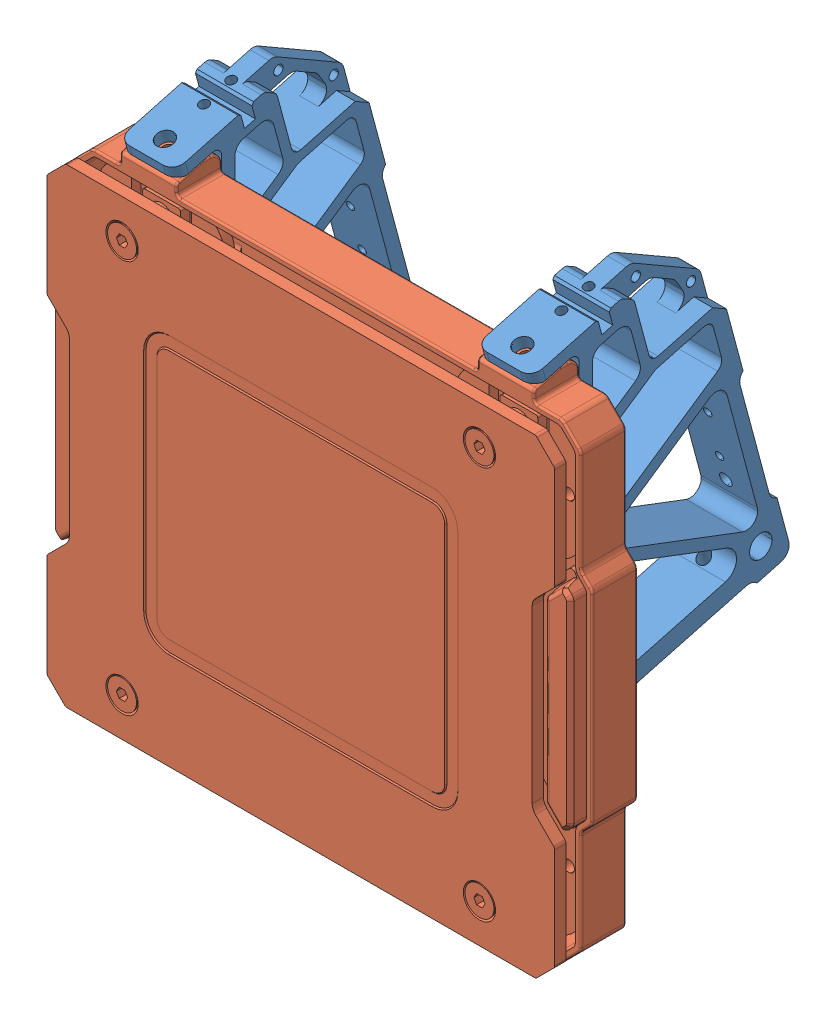
SolidWorks assembly 装配体1, configuration 默认. Lengths in mm.
Overall size (141 139.39 74.83).
3 component instances, 2 part files, 6 mates.
Components (placement in the parent):
- RM2019裁判系统支撑架AH02-1: RM2019裁判系统支撑架AH02 [默认] at (-15.033 -31.1753 152.6103) size (15 130.97 68.39)
- RM2019裁判系统装甲模块AM02-1: RM2019裁判系统装甲模块AM02 [默认] at (-107.5374 -73.9899 179.5172) x (0 0 1) z (-1 0 0) size (19 129.97 141)
- RM2019裁判系统支撑架AH02-2: RM2019裁判系统支撑架AH02 [默认] at (-110.033 -31.1753 152.6103) size (15 130.97 68.39)
Mates (geometry in assembly coordinates):
- 重合1: coincident: plane of assembly; plane of assembly; plane of RM2019裁判系统支撑架AH02-1 through (-7.533 58.8247 152.6103) normal (0 0 1); plane of RM2019裁判系统装甲模块AM02-1 through (-62.533 -10.0287 152.6103) normal (0 0 -1)
- 重合2: coincident: plane of assembly; plane of assembly; plane of RM2019裁判系统装甲模块AM02-1 through (-62.533 -10.0287 152.6103) normal (0 0 -1); plane of RM2019裁判系统支撑架AH02-2 through (-102.533 58.8247 152.6103) normal (0 0 1)
- 重合3: coincident: plane of assembly; plane of assembly; plane of RM2019裁判系统装甲模块AM02-1 through (-102.533 58.6867 152.6103) normal (0 0.965926 0.258819); plane of RM2019裁判系统支撑架AH02-2 through (-131.6523 58.6867 152.6103) normal (0 -0.965926 -0.258819)
- 重合4: coincident: plane of assembly; plane of assembly; plane of RM2019裁判系统支撑架AH02-1 through (-36.6523 58.6867 152.6103) normal (0 -0.965926 -0.258819); plane of RM2019裁判系统装甲模块AM02-1 through (-102.533 58.6867 152.6103) normal (0 0.965926 0.258819)
- 重合5: coincident: plane of assembly; plane of assembly; plane of RM2019裁判系统装甲模块AM02-1 through (-117.533 -10.0287 152.6103) normal (-1 0 0); plane of RM2019裁判系统支撑架AH02-2 through (-117.533 -31.1753 152.6103) normal (-1 0 0)
- 重合6: coincident: plane of assembly; plane of assembly; plane of RM2019裁判系统支撑架AH02-1 through (-22.533 -31.1753 152.6103) normal (-1 0 0); plane of RM2019裁判系统装甲模块AM02-1 through (-22.533 -10.0287 152.6103) normal (-1 0 0)
